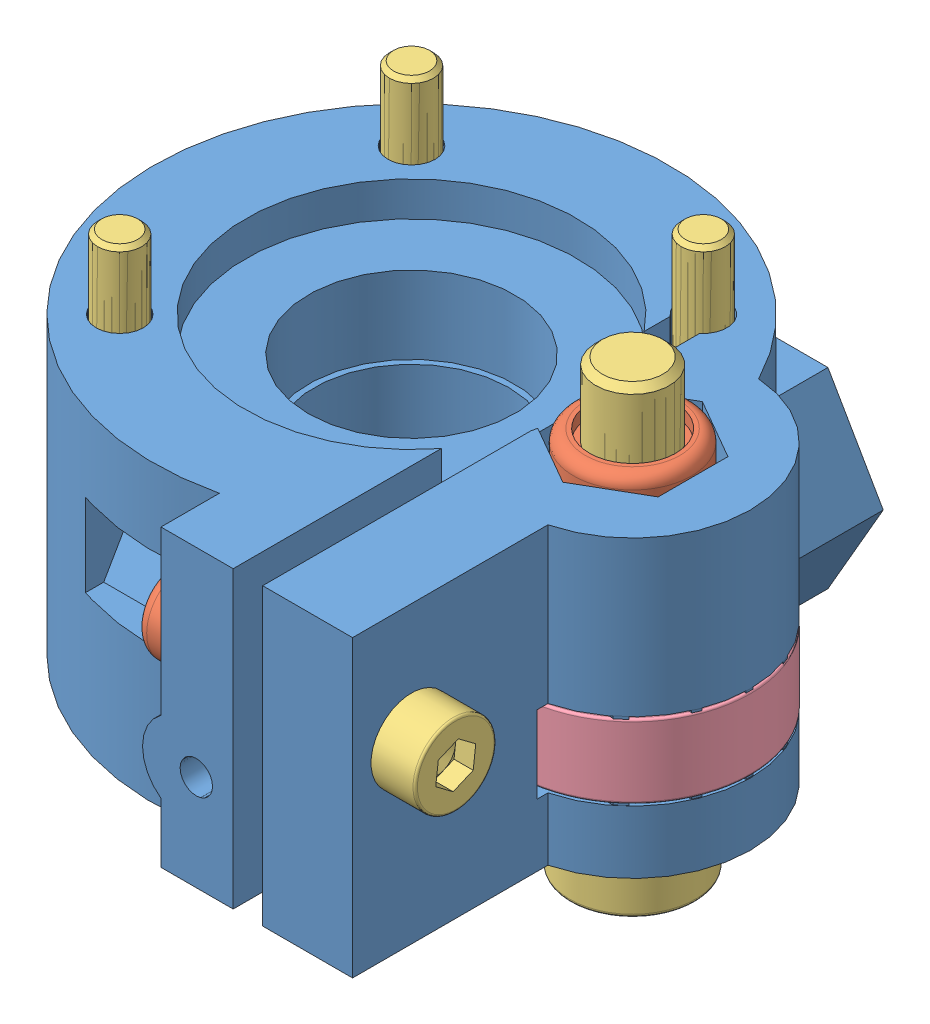
SolidWorks assembly Extruder Assy, configuration Default. Lengths in mm.
Overall size (40.5 30 39).
9 component instances, 4 part files, 18 mates.
Components (placement in the parent):
- Extruder-1: Extruder [Default] at (-22.6402 5.0967 -1.2607) size (40.5 20 39)
- torque nut 01_iso-1: torque nut 01_iso [ISO 7040-M5-C] at (-7.6402 23.4967 -1.2607) x (0.5 0 -0.866025) z (0 1 0) size (8 9.24 6.8)
- socket head cap screw_iso-1: socket head cap screw_iso [ISO 4762 M3 x 25 --- 18C] at (-32.5397 2.0967 8.6388) x (0 1 0) z (0 0 1) size (28 5.5 5.5)
- socket head cap screw_iso-2: socket head cap screw_iso [ISO 4762 M3 x 25 --- 18C] at (-32.5397 2.0967 -11.1602) x (0 1 0) z (0 0 1) size (28 5.5 5.5)
- socket head cap screw_iso-3: socket head cap screw_iso [ISO 4762 M3 x 25 --- 18C] at (-12.7407 2.0967 -11.1602) x (0 1 0) z (0 0 1) size (28 5.5 5.5)
- socket head cap screw_iso-4: socket head cap screw_iso [ISO 4762 M3 x 16 --- 16C] at (-2.6402 17.0967 15.7393) x (-1 0 0) z (0 0.118821 0.992916) size (19 5.5 5.5)
- torque nut 01_iso-2: torque nut 01_iso [ISO 7040-M3-C] at (-19.2902 17.0967 15.7393) x (0 0.5 -0.866025) z (-1 0 0) size (5.5 6.35 4.5)
- socket head cap screw_iso-5: socket head cap screw_iso [ISO 4762 M5 x 25 --- 25C] at (-7.6402 0.0967 -1.2607) x (0 1 0) z (0.99547 0 0.095081) size (30 8.5 8.5)
- 625 2RS-1: 625 2RS [Default] at (-7.6402 9.4467 -1.2607) x (1 0 0) z (0 -1 0) size (16 16 5)
Mates (geometry in assembly coordinates):
- Concentric1: concentric anti-aligned: cylinder of Extruder-1 through (-32.5397 5.0957 8.6388) axis (0 1 0) radius 1.6; cylinder of socket head cap screw_iso-1 through (-32.5397 -29.6533 8.6388) axis (0 -1 0) radius 1.5
- Coincident1: coincident anti-aligned: plane of Extruder-1 through (-7.6402 5.0967 -1.2607) normal (0 -1 0); plane of socket head cap screw_iso-1 through (-35.2897 5.0967 8.6388) normal (0 1 0)
- Concentric21: concentric anti-aligned: cylinder of Extruder-1 through (-32.5397 5.0957 -11.1602) axis (0 1 0) radius 1.6; cylinder of socket head cap screw_iso-2 through (-32.5397 -29.6533 -11.1602) axis (0 -1 0) radius 2.75
- Coincident21: coincident anti-aligned: plane of Extruder-1 through (-7.6402 5.0967 -1.2607) normal (0 -1 0); plane of socket head cap screw_iso-2 through (-35.2897 5.0967 -11.1602) normal (0 1 0)
- Concentric31: concentric anti-aligned: cylinder of Extruder-1 through (-12.7407 5.0957 -11.1602) axis (0 1 0) radius 1.6; cylinder of socket head cap screw_iso-3 through (-12.7407 -29.6533 -11.1602) axis (0 -1 0) radius 2.75
- Coincident31: coincident anti-aligned: plane of Extruder-1 through (-7.6402 5.0967 -1.2607) normal (0 -1 0); plane of socket head cap screw_iso-3 through (-15.4907 5.0967 -11.1602) normal (0 1 0)
- Concentric41: concentric aligned: cylinder of Extruder-1 through (-23.1656 17.0967 15.7393) axis (1 0 0) radius 1.6; cylinder of socket head cap screw_iso-4 through (29.1098 17.0967 15.7393) axis (1 0 0) radius 2.75
- Coincident41: coincident anti-aligned: plane of Extruder-1 through (-5.6402 25.0967 19.7393) normal (1 0 0); plane of socket head cap screw_iso-4 through (-5.6402 14.3661 16.0661) normal (-1 0 0)
- Concentric5: concentric anti-aligned: cylinder of socket head cap screw_iso-4 through (29.1098 17.0967 15.7393) axis (1 0 0) radius 1.5; cylinder of torque nut 01_iso-2 through (-17.1402 17.0967 15.7393) axis (-1 0 0) radius 1.25
- Parallel1: parallel anti-aligned: plane of Extruder-1 through (-28.1402 17.0967 12.5062) normal (0 0.5 0.866025); plane of torque nut 01_iso-2 through (-17.1402 17.0967 12.5639) normal (0 -0.5 -0.866025)
- Coincident6: coincident anti-aligned: plane of Extruder-1 through (-17.1402 5.0967 -1.2607) normal (-1 0 0); plane of torque nut 01_iso-2 through (-17.1402 14.3467 14.1516) normal (1 0 0)
- Concentric6: concentric anti-aligned: cylinder of Extruder-1 through (-7.6402 5.0957 -1.2607) axis (0 1 0) radius 2.6; cylinder of socket head cap screw_iso-5 through (-7.6402 -31.6533 -1.2607) axis (0 -1 0) radius 2.5
- Coincident7: coincident anti-aligned: plane of Extruder-1 through (-7.6402 5.0967 -1.2607) normal (0 -1 0); plane of socket head cap screw_iso-5 through (-8.0443 5.0967 2.9701) normal (0 1 0)
- Concentric7: concentric anti-aligned: cylinder of torque nut 01_iso-1 through (-7.6402 19.0967 -1.2607) axis (0 1 0) radius 2.1; cylinder of socket head cap screw_iso-5 through (-7.6402 -31.6533 -1.2607) axis (0 -1 0) radius 2.5
- Parallel2: parallel anti-aligned: plane of Extruder-1 through (-3.5397 19.0967 -3.6281) normal (-0.5 0 0.866025); plane of torque nut 01_iso-1 through (-7.6402 19.0967 -5.8795) normal (0.5 0 -0.866025)
- Coincident9: coincident anti-aligned: plane of Extruder-1 through (-22.6402 19.0967 -1.2607) normal (0 1 0); plane of torque nut 01_iso-1 through (-11.6402 19.0967 -3.5701) normal (0 -1 0)
- Concentric8: concentric anti-aligned: cylinder of socket head cap screw_iso-5 through (-7.6402 -31.6533 -1.2607) axis (0 -1 0) radius 2.5; cylinder of 625 2RS-1 through (-7.6402 9.4467 -1.2607) axis (0 1 0) radius 2.5
- Distance1: distance = 0.1 mm anti-aligned: plane of 625 2RS-1 through (-7.6402 9.4467 6.5893) normal (0 -1 0); plane of Extruder-1 through (-7.6402 9.3467 -1.2607) normal (0 1 0)
